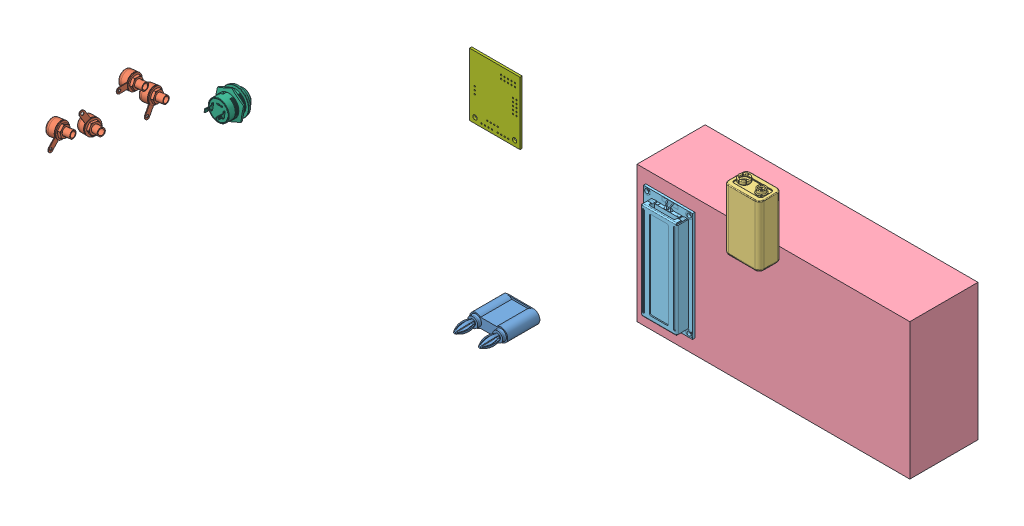
SolidWorks assembly Enclosure, configuration Default. Lengths in mm.
Overall size (415.41 147.84 281.9).
10 component instances, 7 part files, 7 mates.
Components (placement in the parent):
- 11463241 Banana Jack Dual Plug-1: 11463241 Banana Jack Dual Plug [Default] at (-114.2756 -4.4109 85.6578) size (27.94 9.65 39.37)
- 4mm Panel Mount Banana Socket-1: 4mm Panel Mount Banana Socket [Default] at (-306.7927 68.3795 192.4066) x (-0.068922 -0.481702 0.873621) z (-0.980085 -0.130779 -0.149431) size (11 19.1 15)
- Battery 9V-1: Battery 9V [Default] at (0 54.5635 0) size (25.91 48.13 16.26)
- Box-1: Box [Default] x (-1 0 0) z (0 -1 0) size (200 50 100)
- LCD-1: LCD [Default] at (-75.6363 0.7051 0) x (0 1 0) z (1 0 0) size (80 18.3 36)
- PBRED_MODEL1-1: PBRED_MODEL1 [Default] at (-252.1236 85.3347 154.6961) x (0.991097 -0.132993 -0.006323) z (0.132653 0.990404 -0.03876) size (19.5 25 22.17)
- tmtr_board_rev1-1: tmtr_board_rev1 [Default] at (-217.3068 12.1099 0) size (37 46 1.59)
- 4mm Panel Mount Banana Socket-3: 4mm Panel Mount Banana Socket [Default] at (-304.5296 68.5276 151.9512) x (-0.039322 -0.587396 -0.808344) z (-0.993313 -0.064902 0.095482) size (11 19.1 15)
- 4mm Panel Mount Banana Socket-4: 4mm Panel Mount Banana Socket [Default] at (-306.2511 79.2895 218.3581) x (-0.024519 -0.796043 -0.604744) z (-0.992881 -0.051139 0.107573) size (11 19.1 15)
- 4mm Panel Mount Banana Socket-5: 4mm Panel Mount Banana Socket [Default] at (-304.604 85.2331 165.7639) x (0.049483 -0.998199 0.033925) z (-0.99708 -0.047393 0.059876) size (11 19.1 15)
Mates (geometry in assembly coordinates):
- Coincident2: coincident anti-aligned: plane of Box-1; plane of assembly through (0 0 0) normal (0 0 1)
- Coincident3: coincident anti-aligned: plane of Box-1; plane of assembly through (0 0 0) normal (1 0 0)
- Coincident4: coincident aligned: plane of Battery 9V-1 through (0 54.5635 0) normal (1 0 0); plane of assembly through (0 0 0) normal (1 0 0)
- Coincident5: coincident aligned: plane of Battery 9V-1 through (0 54.5635 0) normal (0 0 1); plane of assembly through (0 0 0) normal (0 0 1)
- Coincident6: coincident aligned: plane of tmtr_board_rev1-1 through (-217.3068 12.1099 0) normal (0 0 1); plane of assembly through (0 0 0) normal (0 0 1)
- Coincident10: coincident: point of Box-1; point of assembly
- Coincident14: coincident anti-aligned: plane of Box-1 through (0 0 0) normal (0 0 1); plane of LCD-1 through (-75.6363 0.7051 0) normal (0 0 -1)
